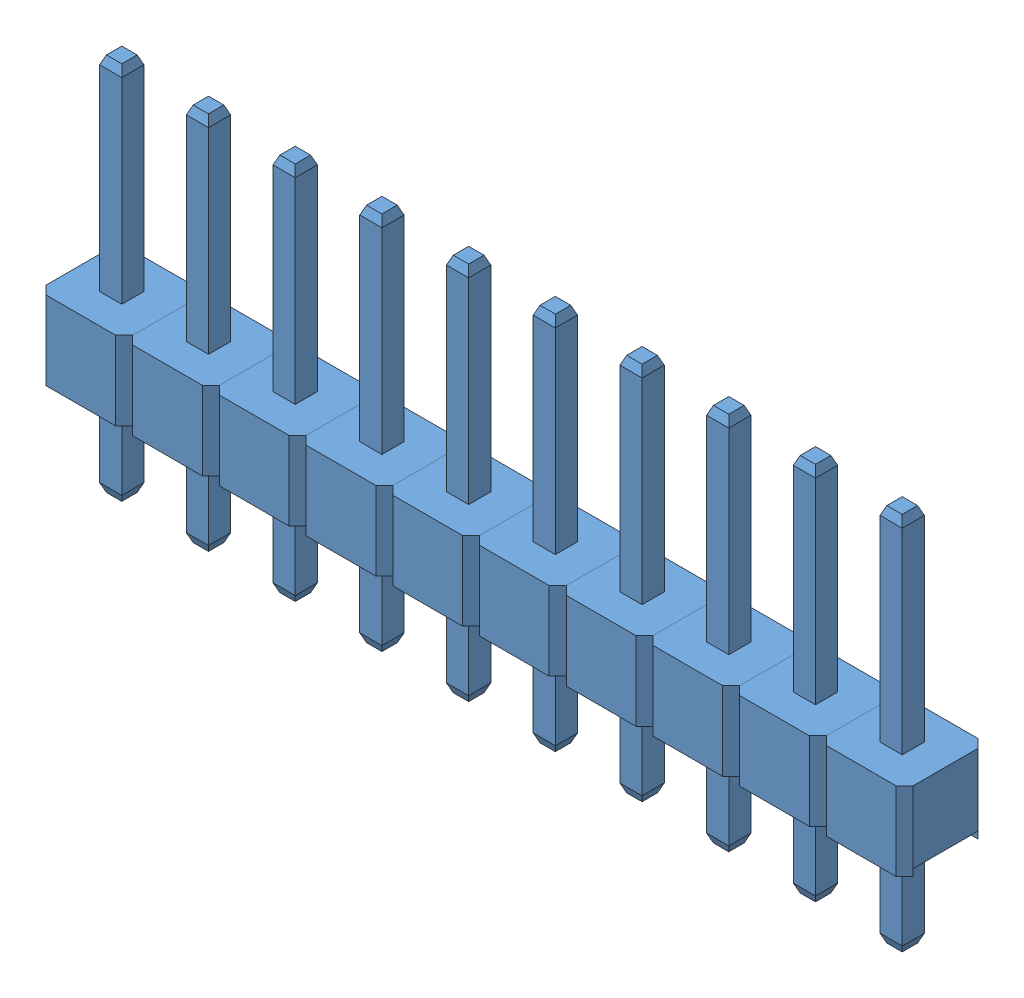
SolidWorks assembly Assem1, configuration Default. Lengths in mm.
Overall size (25.4 11.1 2.4).
10 component instances, 1 part files, 0 mates.
Components (placement in the parent):
- 1_Male_Pin_2.54_mm-1: 1_Male_Pin_2.54_mm [Default] at (3.8763 2.2562 11.0637) size (2.54 11.1 2.4)
- 1_Male_Pin_2.54_mm-2: 1_Male_Pin_2.54_mm [Default] at (1.3363 2.2562 11.0637) size (2.54 11.1 2.4)
- 1_Male_Pin_2.54_mm-3: 1_Male_Pin_2.54_mm [Default] at (-1.2037 2.2562 11.0637) size (2.54 11.1 2.4)
- 1_Male_Pin_2.54_mm-4: 1_Male_Pin_2.54_mm [Default] at (-3.7437 2.2562 11.0637) size (2.54 11.1 2.4)
- 1_Male_Pin_2.54_mm-5: 1_Male_Pin_2.54_mm [Default] at (-6.2837 2.2562 11.0637) size (2.54 11.1 2.4)
- 1_Male_Pin_2.54_mm-6: 1_Male_Pin_2.54_mm [Default] at (-8.8237 2.2562 11.0637) size (2.54 11.1 2.4)
- 1_Male_Pin_2.54_mm-7: 1_Male_Pin_2.54_mm [Default] at (-11.3637 2.2562 11.0637) size (2.54 11.1 2.4)
- 1_Male_Pin_2.54_mm-8: 1_Male_Pin_2.54_mm [Default] at (-13.9037 2.2562 11.0637) size (2.54 11.1 2.4)
- 1_Male_Pin_2.54_mm-9: 1_Male_Pin_2.54_mm [Default] at (-16.4437 2.2562 11.0637) size (2.54 11.1 2.4)
- 1_Male_Pin_2.54_mm-10: 1_Male_Pin_2.54_mm [Default] at (-18.9837 2.2562 11.0637) size (2.54 11.1 2.4)
